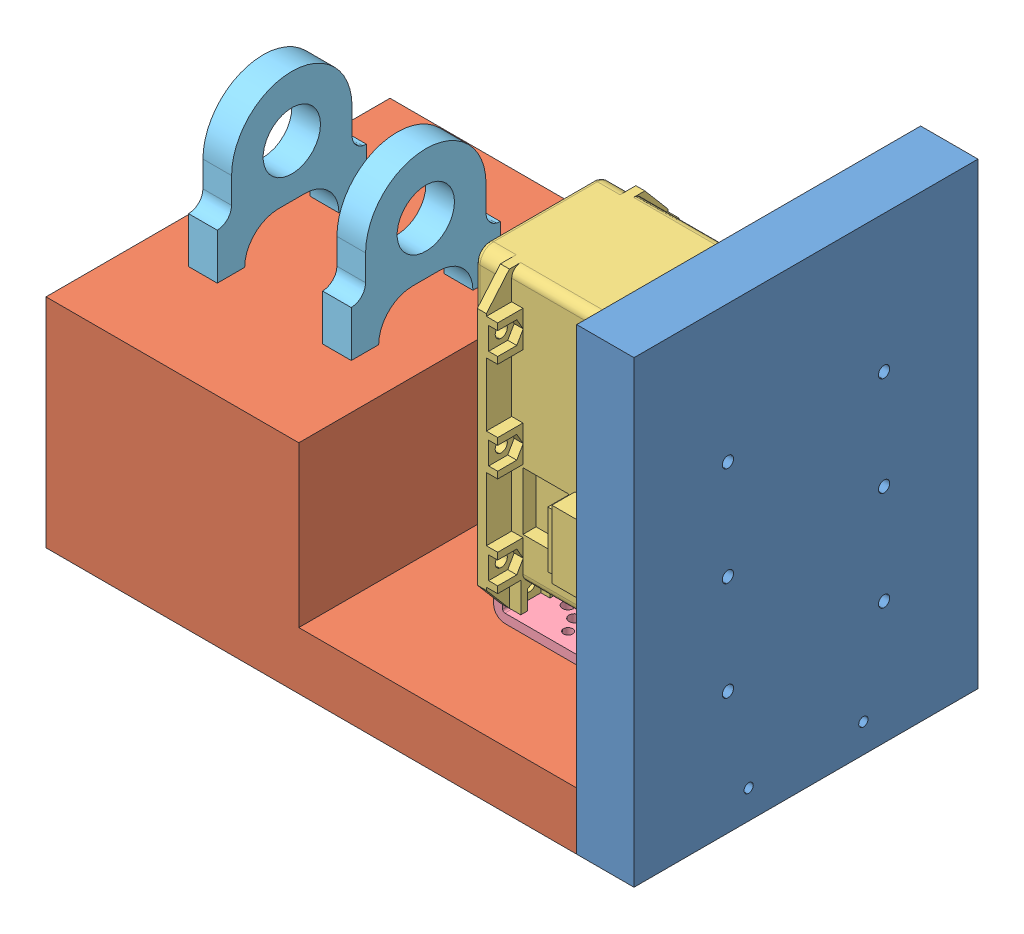
SolidWorks assembly Link1, configuration Default. Lengths in mm.
Overall size (130.25 101.6 76.2).
6 component instances, 5 part files, 15 mates.
Components (placement in the parent):
- Motor1Back-1: Motor1Back [Default] at (-30.237 25.9824 94.4603) size (12.7 101.6 76.2)
- Motor1Bottom-1: Motor1Bottom [Default] at (-30.237 25.4286 94.4603) x (-1 0 0) z (0 0 -1) size (117.55 48.15 76.2)
- EX-106+-1: EX-106+ [Default] at (-53.237 93.1824 94.4603) x (0 0 1) z (-1 0 0) size (40.2 65.92 50.9)
- FR05-S101-1: FR05-S101 [Default] at (-53.237 38.6824 94.4603) x (0 0 1) z (-1 0 0) size (36 9.31 38.02)
- PillowBlock-1: PillowBlock [Default] at (-131.437 93.1824 94.4603) x (0 0 1) z (-1 0 0) size (33.02 32.38 6.35)
- PillowBlock-2: PillowBlock [Default] at (-101.757 93.1824 94.4603) x (0 0 1) z (-1 0 0) size (33.02 32.38 6.35)
Mates (geometry in assembly coordinates):
- Concentric1: concentric: circle of Motor1Back-1; circle of Motor1Bottom-1
- Concentric2: concentric: circle of Motor1Back-1; circle of Motor1Bottom-1
- Coincident1: coincident anti-aligned: plane of Motor1Back-1 through (-30.237 25.9824 94.4603) normal (-1 0 0); plane of Motor1Bottom-1 through (-30.237 25.4286 94.4603) normal (1 0 0)
- Concentric3: concentric: circle of Motor1Bottom-1; circle of FR05-S101-1
- Concentric4: concentric: circle of Motor1Bottom-1; circle of FR05-S101-1
- Coincident2: coincident anti-aligned: plane of Motor1Bottom-1 through (-147.787 38.6824 56.3603) normal (0 1 0); plane of FR05-S101-1 through (-69.737 38.6824 108.9603) normal (0 -1 0)
- Concentric5: concentric: circle of Motor1Bottom-1; circle of PillowBlock-2
- Concentric6: concentric: circle of Motor1Bottom-1; circle of PillowBlock-2
- Coincident3: coincident anti-aligned: plane of Motor1Bottom-1 through (-30.237 74.1324 94.4603) normal (0 1 0); plane of PillowBlock-2 through (-108.107 74.1324 77.9503) normal (0 -1 0)
- Concentric7: concentric: circle of Motor1Bottom-1; circle of PillowBlock-1
- Concentric8: concentric: circle of Motor1Bottom-1; circle of PillowBlock-1
- Coincident4: coincident anti-aligned: plane of Motor1Bottom-1 through (-30.237 74.1324 94.4603) normal (0 1 0); plane of PillowBlock-1 through (-137.787 74.1324 77.9503) normal (0 -1 0)
- Concentric9: concentric: circle of EX-106+-1; circle of FR05-S101-1
- Concentric10: concentric: circle of EX-106+-1; circle of FR05-S101-1
- Coincident5: coincident anti-aligned: plane of EX-106+-1 through (-36.237 93.1824 94.4603) normal (1 0 0); plane of FR05-S101-1 through (-36.237 41.1824 108.9603) normal (-1 0 0)
